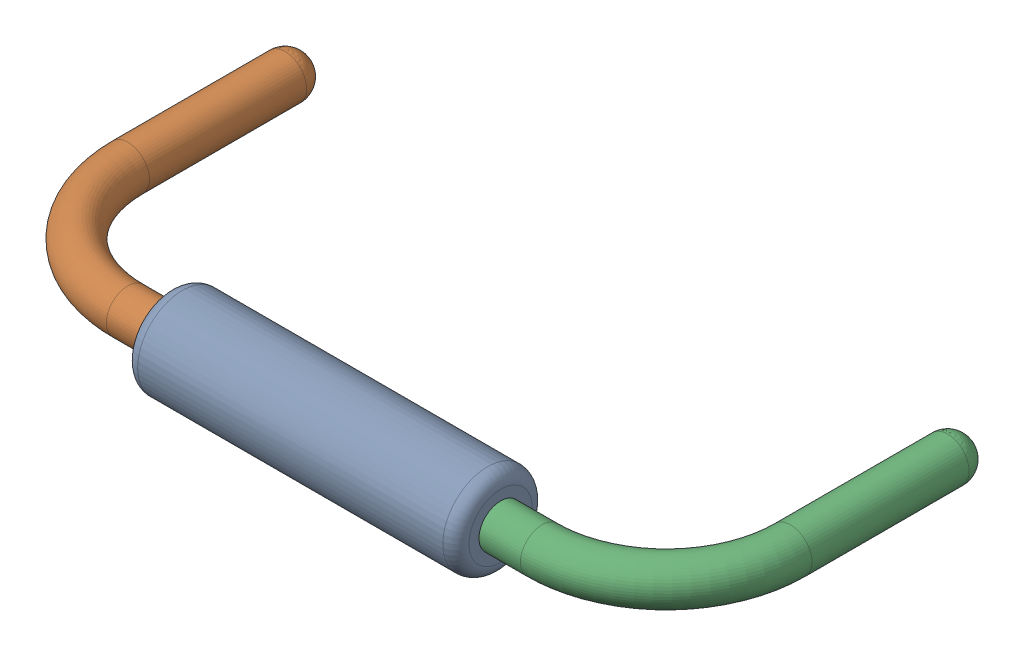
SolidWorks assembly R8, configuration Défaut. Lengths in mm.
Overall size (10.82 1.37 5.33).
4 component instances, 3 part files, 0 mates.
Components (placement in the parent):
- Open CASCADE STEP translator 6.8 1.10.1-1: Open CASCADE STEP translator 6.8 1.10.1 [Défaut] at origin size (10.82 1.37 5.33)
  - Body_1_7-1: Body_1_7 [Défaut] at origin size (5.08 1.37 1.37)
  - Pin_1_4-1: Pin_1_4 [Défaut] at origin size (3.2 0.66 4.98)
  - Pin_2_4-1: Pin_2_4 [Défaut] at (20.32 0 0) x (-1 0 0) z (0 0 1) size (3.2 0.66 4.98)
